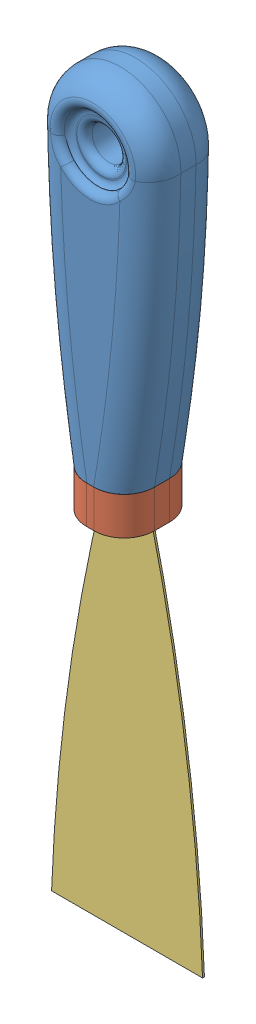
SolidWorks assembly Spartel_Complete_40mm, configuration Default. Lengths in mm.
Overall size (40 202.81 20.12).
4 component instances, 3 part files, 0 mates.
Components (placement in the parent):
- Spartel_Complete_40mm.stp-1: Spartel_Complete_40mm.stp [Default] at origin size (40 202.81 20.12)
  - E5ndtag.stp-1: E5ndtag.stp [Default] at origin size (33.78 96.21 20.12)
  - Ring.stp-1: Ring.stp [Default] at (-9.0007 -76.0025 20) x (1 0 0) z (0 -1 0) size (18 20 10)
  - Blad.stp-1: Blad.stp [Default] at (-20.0007 -183.9751 10.25) x (1 0 0) z (0 0 -1) size (40 99.97 0.5)
